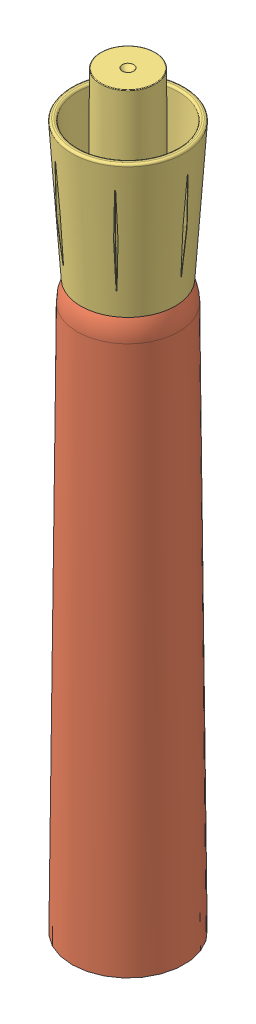
SolidWorks assembly EM-COMPLETED MARKER, configuration Default. Lengths in mm.
Overall size (22.53 123.53 22.53).
5 component instances, 5 part files, 9 mates.
Components (placement in the parent):
- EM-TIP-1: EM-TIP [Default] at (-28.5306 58.9734 41.2191) x (-0.333247 0 -0.942839) z (0.942839 0 -0.333247) size (6.14 40.54 3.7)
- EM-HOUSING-1: EM-HOUSING [Default] at (-26.7419 -40.0322 40.7284) size (18.51 113.74 18.51)
- EM-CAP-1: EM-CAP [Default] at (-26.7419 53.3423 40.7284) x (0.995537 0 -0.094372) z (0.094372 0 0.995537) size (18.55 30.16 18.55)
- EM-END CAP-1: EM-END CAP [Default] at (-26.7419 -32.1122 40.7284) x (0.885678 0 -0.464299) z (-0.464299 0 -0.885678) size (16.69 10.84 16.69)
- EM-INK-1: EM-INK [Default] at (-26.7419 50.3214 40.7284) x (0.333247 0 0.942839) z (0.942839 0 -0.333247) size (12.79 80.99 12.79)
Mates (geometry in assembly coordinates):
- Concentric1: concentric: cone of EM-HOUSING-1 through (-26.7419 49.9678 40.7284) axis (0 1 0); cylinder of EM-END CAP-1 through (-26.7419 -40.0322 40.7284) axis (0 1 0) radius 8.345
- Coincident1: coincident: plane of EM-HOUSING-1 through (-26.7419 -40.0322 40.7284) normal (0 -1 0); plane of EM-END CAP-1 through (-26.7419 -40.0322 40.7284) normal (0 -1 0)
- Concentric2: concentric: cone of EM-HOUSING-1 through (-26.7419 56.2984 40.7284) axis (0 1 0); cone of EM-CAP-1 through (-26.7419 82.5023 40.7284) axis (0 1 0)
- Coincident2: coincident: plane of EM-TIP-1 through (-23.9746 77.8214 43.0064) normal (0.333247 0 0.942839); plane of EM-INK-1 through (-27.4631 41.8214 44.2394) normal (-0.333247 0 -0.942839)
- Coincident3: coincident: plane of EM-TIP-1 through (-25.0421 58.9734 39.986) normal (0.942839 0 -0.333247); plane of EM-INK-1 through (-26.0207 41.8214 37.2174) normal (-0.942839 0 0.333247)
- Concentric4: concentric: cone of EM-HOUSING-1 through (-26.7419 49.9678 40.7284) axis (0 1 0); cylinder of EM-INK-1 through (-26.7419 -30.6686 40.7284) axis (0 1 0) radius 6.395
- Coincident9: coincident: plane of EM-TIP-1 through (26.8575 61.6844 18.5275) normal (0 -1 0); plane of EM-HOUSING-1 through (-23.3055 61.6844 40.7284) normal (0 1 0)
- Coincident11: coincident: line of EM-TIP-1 through (-24.8231 41.8214 43.3063) axis (-0.942839 0 0.333247); line of EM-INK-1 through (-27.4631 41.8214 44.2394) axis (0.942839 0 -0.333247)
- Tangent1: tangent: torus of EM-HOUSING-1; circle of EM-CAP-1
